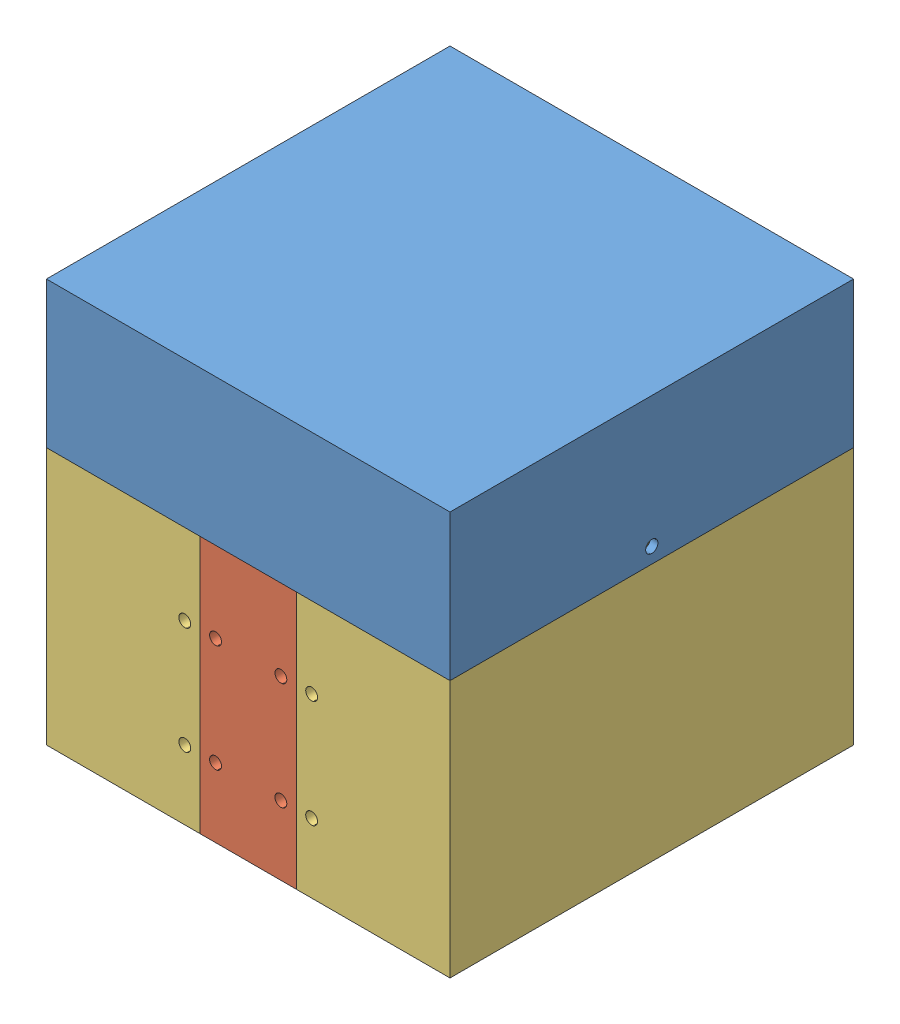
SolidWorks assembly 1.2box, configuration Default. Lengths in mm.
Overall size (105 105 105).
4 component instances, 3 part files, 3 mates.
Components (placement in the parent):
- 1.1top-1: 1.1top [Default] at (34.3923 98.3457 68.1303) x (-1 0 0) z (0 0 1) size (105 38 105)
- 1.2middle-1: 1.2middle [Default] at (34.3923 -4.6543 68.1303) size (25 75 105)
- 1.2rx-1: 1.2rx [Default] at (1.8923 -6.6543 68.1303) size (40 75 105)
- 1.2rx-2: 1.2rx [Default] at (66.8923 -6.6543 68.1303) x (-1 0 0) z (0 0 -1) size (40 75 105)
Mates (geometry in assembly coordinates):
- Coincident1: coincident: point of 1.2middle-1; point of 1.2rx-1
- Coincident2: coincident: point of 1.2middle-1; point of 1.2rx-2
- Coincident4: coincident: point of 1.1top-1; point of 1.2rx-2
